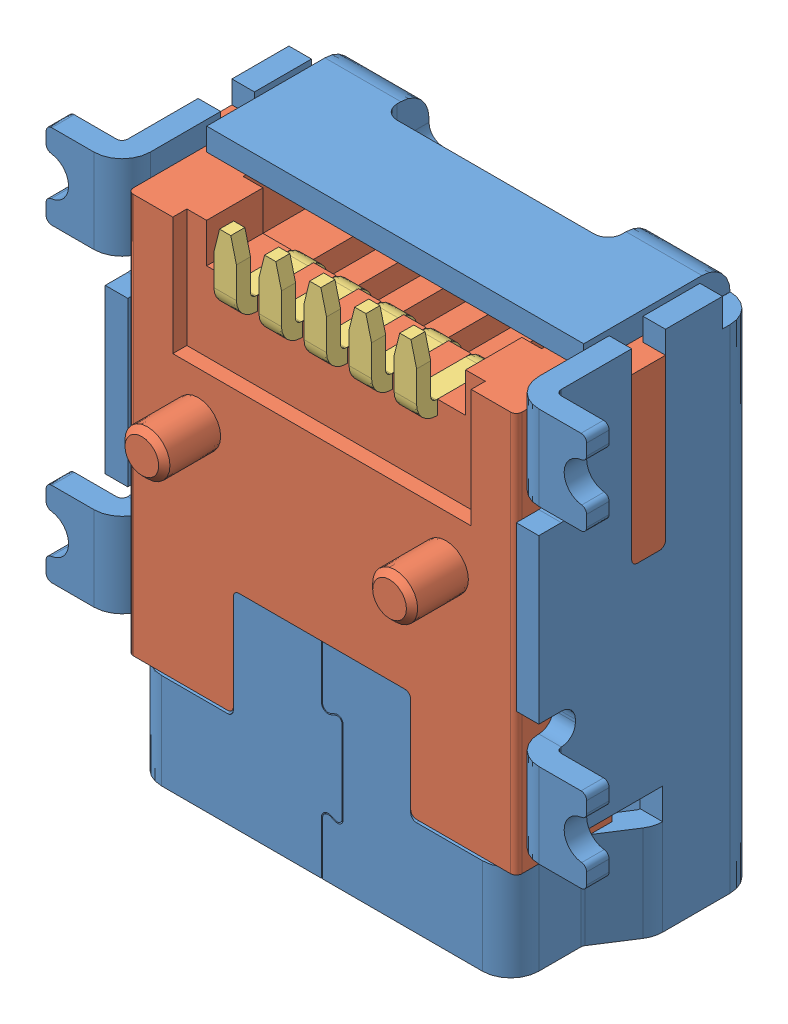
SolidWorks assembly usb_mini_b, configuration Default. Lengths in mm.
Overall size (9.6 9.25 4.91).
7 component instances, 3 part files, 0 mates.
Components (placement in the parent):
- Shielding-1: Shielding [Default] at origin size (9.6 9.25 4.01)
- Insulator-1: Insulator [Default] at (0 2.75 0.2) size (7.7 7.5 4.5)
- Pin_1-1: Pin_1 [Default] at (-1.6 2.225 0.575) size (0.4 7.85 3.02)
- Pin_1-2: Pin_1 [Default] at (-0.8 2.225 0.575) size (0.4 7.85 3.02)
- Pin_1-3: Pin_1 [Default] at (0 2.225 0.575) size (0.4 7.85 3.02)
- Pin_1-4: Pin_1 [Default] at (0.8 2.225 0.575) size (0.4 7.85 3.02)
- Pin_1-5: Pin_1 [Default] at (1.6 2.225 0.575) size (0.4 7.85 3.02)
